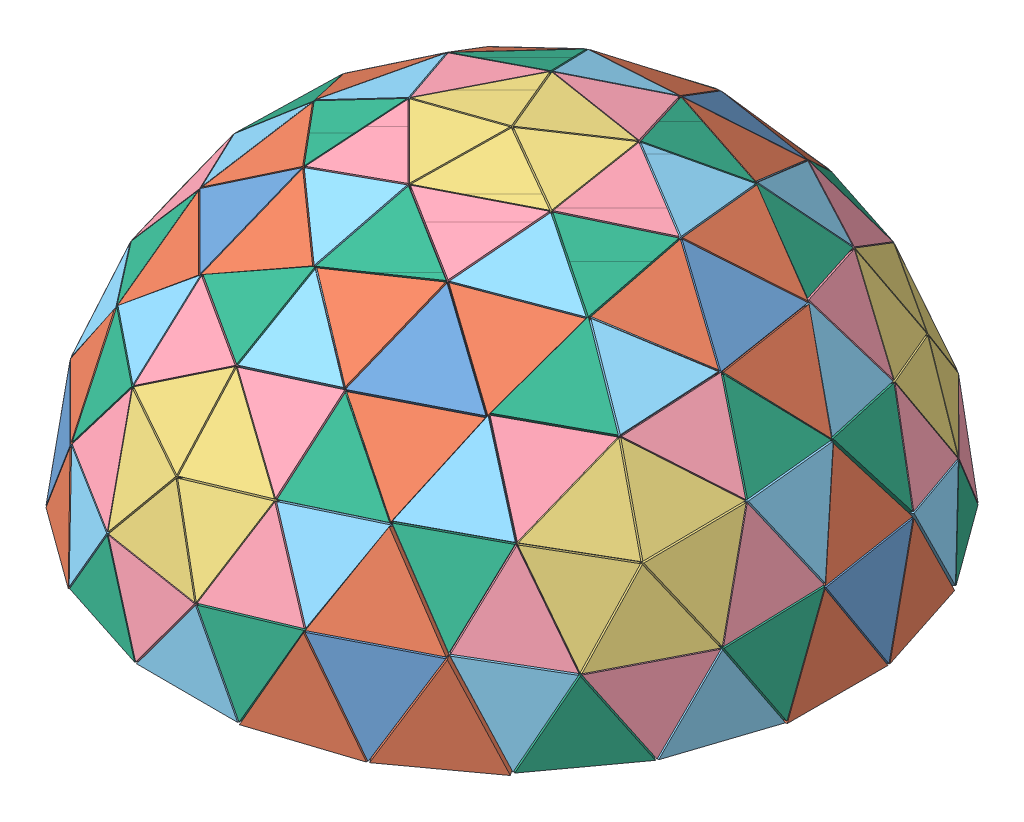
SolidWorks assembly 4Vcorrection, configuration Default. Lengths in mm.
Overall size (6989.16 6215.13 7052.19).
240 component instances, 6 part files, 18 mates.
Components (placement in the parent):
- CCC^4Vcorrection-1: CCC^4Vcorrection [Default] at (5148.8544 1241.364 -148.3819) x (0.61992 0.559911 0.549726) z (-0.217119 -0.550832 0.805881) size (736.35 730.41 804.84) (virtual)
- AAC^4Vcorrection-1: AAC^4Vcorrection [Default] at (1003.1437 19.7447 -1471.5178) x (-0.000489 -0.000047 -1) z (0.99533 0.09653 -0.000491) size (938.64 833.07 70.46) (virtual)
- FFE^4Vcorrection-1: FFE^4Vcorrection [Default] at (-5600.516 7252.777 -2822.5483) x (0.186193 0.133009 -0.973469) z (0.267365 0.946545 0.180468) size (827.41 790.19 223.03) (virtual)
- BBE^4Vcorrection-1: BBE^4Vcorrection [Default] at (-5187.0728 4686.9327 1618.959) x (-0.998714 -0.045499 -0.022385) z (0.046496 -0.997846 -0.046278) size (860.32 848.63 285.86) (virtual)
- ABD^4Vcorrection-2: ABD^4Vcorrection [Default] at (-8587.5048 5777.0189 2775.2885) x (-0.624268 -0.021342 0.780919) z (0.059066 -0.998055 0.019942) size (875.87 755.47 445.29) (virtual)
- ABD_MIRROR^4Vcorrection-1: ABD_MIRROR^4Vcorrection [Default] at (1402.3648 4874.5263 -349.4587) x (0.99908 -0.011123 -0.041412) z (0.039506 0.61429 0.788091) size (875.59 768.38 441.84) (virtual)
- CCC^4Vcorrection-31: CCC^4Vcorrection [Default] at (1449.9639 1241.364 -4942.7041) x (0.714386 0.559911 -0.419705) z (0.699345 -0.550832 0.455523) size (736.35 730.41 804.84) (virtual)
- CCC^4Vcorrection-32: CCC^4Vcorrection [Default] at (-4252.7274 1241.364 -2906.3772) x (-0.178406 0.559911 -0.809117) z (0.649338 -0.550832 -0.524352) size (736.35 730.41 804.84) (virtual)
- CCC^4Vcorrection-33: CCC^4Vcorrection [Default] at (-4078.294 1241.364 3146.4642) x (-0.824647 0.559911 -0.080357) z (-0.298032 -0.550832 -0.779591) size (736.35 730.41 804.84) (virtual)
- CCC^4Vcorrection-34: CCC^4Vcorrection [Default] at (1732.2031 1241.364 4850.999) x (-0.331254 0.559911 0.759454) z (-0.833532 -0.550832 0.042538) size (736.35 730.41 804.84) (virtual)
- AAC^4Vcorrection-101: AAC^4Vcorrection [Default] at (1485.5308 -774.2041 604.8619) x (0.385614 -0.797118 0.464656) z (0.921236 0.360604 -0.145909) size (938.64 833.07 70.46) (virtual)
- AAC^4Vcorrection-130: AAC^4Vcorrection [Default] at (1012.6606 1431.4903 312.0988) x (0.060682 0.883368 0.464735) z (0.946767 0.09653 -0.307106) size (938.64 833.07 70.46) (virtual)
- AAC^4Vcorrection-131: AAC^4Vcorrection [Default] at (1611.8244 210.7493 -727.7764) x (0.701451 -0.406472 -0.585445) z (0.543824 0.836189 0.07102) size (938.64 833.07 70.46) (virtual)
- CCC^4Vcorrection-26: CCC^4Vcorrection [Default] at (3250.1059 4014.1834 -1181.8827) x (0.626993 0.22033 -0.747217) z (-0.756223 -0.058225 -0.651719) size (736.35 730.41 804.84) (virtual)
- AAC^4Vcorrection-104: AAC^4Vcorrection [Default] at (-207.4568 1573.9434 -807.289) x (-0.649291 0.632125 -0.422893) z (0.730552 0.672982 -0.115708) size (938.64 833.07 70.46) (virtual)
- AAC^4Vcorrection-140: AAC^4Vcorrection [Default] at (759.5765 1083.2561 1192.3303) x (0.223363 0.139508 0.9647) z (0.495261 0.836189 -0.235595) size (938.64 833.07 70.46) (virtual)
- AAC^4Vcorrection-136: AAC^4Vcorrection [Default] at (609.753 1431.4903 -866.6536) x (0.460741 0.883368 0.085899) z (0.000491 0.09653 -0.99533) size (938.64 833.07 70.46) (virtual)
- AAC^4Vcorrection-137: AAC^4Vcorrection [Default] at (-635.8125 1431.4903 -847.7202) x (0.224072 0.883368 -0.411646) z (-0.946463 0.09653 -0.308041) size (938.64 833.07 70.46) (virtual)
- AAC^4Vcorrection-138: AAC^4Vcorrection [Default] at (-1002.7067 1431.4903 342.7337) x (-0.322257 0.883368 -0.340311) z (-0.585438 0.09653 0.80495) size (938.64 833.07 70.46) (virtual)
- AAC^4Vcorrection-139: AAC^4Vcorrection [Default] at (16.1057 1431.4903 1059.5413) x (-0.423238 0.883368 0.201323) z (0.584643 0.09653 0.805528) size (938.64 833.07 70.46) (virtual)
- AAC^4Vcorrection-126: AAC^4Vcorrection [Default] at (1034.3121 -774.2041 -1225.9111) x (0.561075 -0.797118 -0.223154) z (0.145909 0.360604 -0.921236) size (938.64 833.07 70.46) (virtual)
- AAC^4Vcorrection-127: AAC^4Vcorrection [Default] at (-846.2907 -774.2041 -1362.5167) x (-0.03885 -0.797118 -0.602573) z (-0.831059 0.360604 -0.423446) size (938.64 833.07 70.46) (virtual)
- AAC^4Vcorrection-128: AAC^4Vcorrection [Default] at (-1557.3486 -774.2041 383.8295) x (-0.585086 -0.797118 -0.149256) z (-0.659532 0.360604 0.659532) size (938.64 833.07 70.46) (virtual)
- AAC^4Vcorrection-129: AAC^4Vcorrection [Default] at (-116.2036 -774.2041 1599.7364) x (-0.322753 -0.797118 0.510327) z (0.423446 0.360604 0.831059) size (938.64 833.07 70.46) (virtual)
- AAC^4Vcorrection-145: AAC^4Vcorrection [Default] at (-1089.5081 19.7447 -1408.7704) x (-0.951208 -0.000047 -0.308552) z (0.307106 0.09653 -0.946767) size (938.64 833.07 70.46) (virtual)
- AAC^4Vcorrection-146: AAC^4Vcorrection [Default] at (-1676.4968 19.7447 600.8498) x (-0.587389 -0.000047 0.809304) z (-0.805528 0.09653 -0.584643) size (938.64 833.07 70.46) (virtual)
- AAC^4Vcorrection-147: AAC^4Vcorrection [Default] at (53.3761 19.7447 1780.116) x (0.588181 -0.000047 0.808729) z (-0.80495 0.09653 0.585438) size (938.64 833.07 70.46) (virtual)
- AAC^4Vcorrection-148: AAC^4Vcorrection [Default] at (1709.485 19.7447 499.3224) x (0.950905 -0.000047 -0.309482) z (0.308041 0.09653 0.946463) size (938.64 833.07 70.46) (virtual)
- AAC^4Vcorrection-132: AAC^4Vcorrection [Default] at (-194.0754 210.7493 -1757.8314) x (-0.340031 -0.406472 -0.848032) z (0.235595 0.836189 -0.495261) size (938.64 833.07 70.46) (virtual)
- AAC^4Vcorrection-133: AAC^4Vcorrection [Default] at (-1731.7696 210.7493 -358.6231) x (-0.911602 -0.406472 0.061332) z (-0.398218 0.836189 -0.377108) size (938.64 833.07 70.46) (virtual)
- AAC^4Vcorrection-134: AAC^4Vcorrection [Default] at (-876.2171 210.7493 1536.1901) x (-0.22337 -0.406472 0.885938) z (-0.481707 0.836189 0.262195) size (938.64 833.07 70.46) (virtual)
- AAC^4Vcorrection-135: AAC^4Vcorrection [Default] at (1190.2376 210.7493 1308.0408) x (0.773552 -0.406472 0.486207) z (0.100507 0.836189 0.539154) size (938.64 833.07 70.46) (virtual)
- CCC^4Vcorrection-27: CCC^4Vcorrection [Default] at (-119.6993 4014.1834 -3456.2562) x (-0.516894 0.22033 -0.827209) z (-0.853507 -0.058225 0.517818) size (736.35 730.41 804.84) (virtual)
- CCC^4Vcorrection-28: CCC^4Vcorrection [Default] at (-3324.0841 4014.1834 -954.2011) x (-0.946452 0.22033 0.235974) z (0.228726 -0.058225 0.971748) size (736.35 730.41 804.84) (virtual)
- CCC^4Vcorrection-29: CCC^4Vcorrection [Default] at (-1934.6977 4014.1834 2866.5275) x (-0.068045 0.22033 0.973049) z (0.994868 -0.058225 0.082755) size (736.35 730.41 804.84) (virtual)
- CCC^4Vcorrection-30: CCC^4Vcorrection [Default] at (2128.3752 4014.1834 2725.8125) x (0.904398 0.22033 0.365403) z (0.386136 -0.058225 -0.920603) size (736.35 730.41 804.84) (virtual)
- AAC^4Vcorrection-122: AAC^4Vcorrection [Default] at (-831.8851 1573.9434 -52.1629) x (-0.602838 0.632125 0.486832) z (0.115708 0.672982 -0.730552) size (938.64 833.07 70.46) (virtual)
- AAC^4Vcorrection-123: AAC^4Vcorrection [Default] at (-306.6765 1573.9434 775.0505) x (0.276717 0.632125 0.723772) z (-0.659041 0.672982 -0.335798) size (938.64 833.07 70.46) (virtual)
- AAC^4Vcorrection-124: AAC^4Vcorrection [Default] at (642.3486 1573.9434 531.1705) x (0.773858 0.632125 -0.039516) z (-0.523018 0.672982 0.523018) size (938.64 833.07 70.46) (virtual)
- AAC^4Vcorrection-125: AAC^4Vcorrection [Default] at (703.6698 1573.9434 -446.7691) x (0.201554 0.632125 -0.748194) z (0.335798 0.672982 0.659041) size (938.64 833.07 70.46) (virtual)
- AAC^4Vcorrection-141: AAC^4Vcorrection [Default] at (1368.6955 1083.2561 -353.9498) x (0.986507 0.139508 0.085677) z (-0.07102 0.836189 -0.543824) size (938.64 833.07 70.46) (virtual)
- AAC^4Vcorrection-142: AAC^4Vcorrection [Default] at (86.3239 1083.2561 -1411.0833) x (0.386332 0.139508 -0.911748) z (-0.539154 0.836189 -0.100507) size (938.64 833.07 70.46) (virtual)
- AAC^4Vcorrection-143: AAC^4Vcorrection [Default] at (-1315.3444 1083.2561 -518.1476) x (-0.747741 0.139508 -0.649169) z (-0.262195 0.836189 0.481707) size (938.64 833.07 70.46) (virtual)
- AAC^4Vcorrection-144: AAC^4Vcorrection [Default] at (-899.2515 1083.2561 1090.8505) x (-0.848461 0.139508 0.51054) z (0.377108 0.836189 0.398218) size (938.64 833.07 70.46) (virtual)
- ABD^4Vcorrection-53: ABD^4Vcorrection [Default] at (-14.2287 5777.0189 9024.8137) x (0.549789 -0.021342 0.835031) z (0.037218 -0.998055 -0.050013) size (875.87 755.47 445.29) (virtual)
- ABD^4Vcorrection-114: ABD^4Vcorrection [Default] at (8578.711 5777.0189 2802.3531) x (0.964056 -0.021342 -0.264841) z (-0.036064 -0.998055 -0.050851) size (875.87 755.47 445.29) (virtual)
- ABD^4Vcorrection-124: ABD^4Vcorrection [Default] at (5316.1637 5777.0189 -7292.8643) x (0.04603 -0.021342 -0.998712) z (-0.059507 -0.998055 0.018585) size (875.87 755.47 445.29) (virtual)
- ABD^4Vcorrection-134: ABD^4Vcorrection [Default] at (-5293.1411 5777.0189 -7309.5911) x (-0.935607 -0.021342 -0.352396) z (-0.000713 -0.998055 0.062338) size (875.87 755.47 445.29) (virtual)
- ABD_MIRROR^4Vcorrection-37: ABD_MIRROR^4Vcorrection [Default] at (100.9996 4874.5263 -1441.7169) x (0.269347 -0.011123 -0.962979) z (0.761727 0.61429 0.205961) size (875.59 768.38 441.84) (virtual)
- ABD_MIRROR^4Vcorrection-98: ABD_MIRROR^4Vcorrection [Default] at (-1339.9436 4874.5263 -541.5713) x (-0.832614 -0.011123 -0.553741) z (0.431267 0.61429 -0.660799) size (875.59 768.38 441.84) (virtual)
- ABD_MIRROR^4Vcorrection-108: ABD_MIRROR^4Vcorrection [Default] at (-929.1303 4874.5263 1107.0074) x (-0.783931 -0.011123 0.620748) z (-0.495189 0.61429 -0.614358) size (875.59 768.38 441.84) (virtual)
- ABD_MIRROR^4Vcorrection-118: ABD_MIRROR^4Vcorrection [Default] at (765.7096 4874.5263 1225.7395) x (0.348118 -0.011123 0.937385) z (-0.737311 0.61429 0.281105) size (875.59 768.38 441.84) (virtual)
- BBE^4Vcorrection-31: BBE^4Vcorrection [Default] at (-63.1721 4686.9327 5433.4852) x (-0.329909 -0.045499 0.942916) z (-0.029645 -0.997846 -0.058521) size (860.32 848.63 285.86) (virtual)
- BBE^4Vcorrection-92: BBE^4Vcorrection [Default] at (5148.0302 4686.9327 1739.1195) x (0.794819 -0.045499 0.605139) z (-0.064818 -0.997846 0.01011) size (860.32 848.63 285.86) (virtual)
- BBE^4Vcorrection-102: BBE^4Vcorrection [Default] at (3244.8298 4686.9327 -4358.6502) x (0.821134 -0.045499 -0.568919) z (-0.010415 -0.997846 0.064769) size (860.32 848.63 285.86) (virtual)
- BBE^4Vcorrection-112: BBE^4Vcorrection [Default] at (-3142.6151 4686.9327 -4432.9135) x (-0.28733 -0.045499 -0.95675) z (0.058381 -0.997846 0.02992) size (860.32 848.63 285.86) (virtual)
- FFE^4Vcorrection-27: FFE^4Vcorrection [Default] at (-4415.0576 7252.777 4454.1919) x (-0.868287 0.133009 -0.477898) z (0.254256 0.946545 -0.198512) size (827.41 790.19 223.03) (virtual)
- FFE^4Vcorrection-88: FFE^4Vcorrection [Default] at (2871.8604 7252.777 5575.3903) x (-0.722823 0.133009 0.678111) z (-0.110226 0.946545 -0.303155) size (827.41 790.19 223.03) (virtual)
- FFE^4Vcorrection-98: FFE^4Vcorrection [Default] at (6189.9649 7252.777 -1008.4112) x (0.421558 0.133009 0.896994) z (-0.322379 0.946545 0.011151) size (827.41 790.19 223.03) (virtual)
- FFE^4Vcorrection-108: FFE^4Vcorrection [Default] at (953.7484 7252.777 -6198.6227) x (0.98336 0.133009 -0.123739) z (-0.089015 0.946545 0.310047) size (827.41 790.19 223.03) (virtual)
- ABD^4Vcorrection-144: ABD^4Vcorrection [Default] at (7466.3779 6226.7147 4505.8449) x (0.554978 0.76321 -0.330922) z (0.075466 -0.442359 -0.893657) size (875.87 755.47 445.29) (virtual)
- ABD_MIRROR^4Vcorrection-128: ABD_MIRROR^4Vcorrection [Default] at (-2017.2487 1708.941 4342.8083) x (-0.981501 -0.177094 -0.072755) z (-0.187221 0.967276 0.171244) size (875.59 768.38 441.84) (virtual)
- BBE^4Vcorrection-122: BBE^4Vcorrection [Default] at (4352.124 4252.7353 3803.5969) x (0.994073 0.095186 0.052524) z (0.093298 -0.498914 -0.861615) size (860.32 848.63 285.86) (virtual)
- FFE^4Vcorrection-118: FFE^4Vcorrection [Default] at (4777.7299 1556.6671 8166.114) x (-0.121759 -0.822885 0.555008) z (-0.407266 0.551349 0.728113) size (827.41 790.19 223.03) (virtual)
- ABD^4Vcorrection-78: ABD^4Vcorrection [Default] at (-1512.6158 10570.6712 891.2438) x (-0.608653 0.651589 -0.452741) z (0.102795 -0.501041 -0.859297) size (875.87 755.47 445.29) (virtual)
- ABD^4Vcorrection-115: ABD^4Vcorrection [Default] at (-9484.5166 3921.3023 3080.3808) x (-0.927145 -0.373861 0.025123) z (0.175217 -0.491836 -0.852875) size (875.87 755.47 445.29) (virtual)
- ABD^4Vcorrection-125: ABD^4Vcorrection [Default] at (-5432.4284 -4532.1902 8047.943) x (0.039648 -0.896002 0.442277) z (0.192648 -0.427466 -0.883267) size (875.87 755.47 445.29) (virtual)
- ABD^4Vcorrection-135: ABD^4Vcorrection [Default] at (5043.8005 -3107.3671 8928.9282) x (0.95565 -0.193254 0.222229) z (0.130998 -0.396887 -0.908471) size (875.87 755.47 445.29) (virtual)
- ABD_MIRROR^4Vcorrection-62: ABD_MIRROR^4Vcorrection [Default] at (-642.4774 922.9937 4958.3325) x (-0.185167 -0.890187 0.416269) z (-0.852377 0.356291 0.382767) size (875.59 768.38 441.84) (virtual)
- ABD_MIRROR^4Vcorrection-99: ABD_MIRROR^4Vcorrection [Default] at (706.1181 1911.7465 4657.9371) x (0.869148 -0.380032 0.316477) z (-0.454767 -0.362683 0.813418) size (875.59 768.38 441.84) (virtual)
- ABD_MIRROR^4Vcorrection-109: ABD_MIRROR^4Vcorrection [Default] at (164.8246 3308.7767 3856.7583) x (0.724415 0.648354 -0.234221) z (0.456126 -0.196048 0.868052) size (875.59 768.38 441.84) (virtual)
- ABD_MIRROR^4Vcorrection-119: ABD_MIRROR^4Vcorrection [Default] at (-1518.3086 3183.436 3661.998) x (-0.419349 0.773777 -0.47478) z (0.621478 0.625912 0.471167) size (875.59 768.38 441.84) (virtual)
- BBE^4Vcorrection-56: BBE^4Vcorrection [Default] at (-1020.7958 6918.9452 1606.3199) x (0.254295 0.855087 -0.451842) z (0.169482 -0.499371 -0.849649) size (860.32 848.63 285.86) (virtual)
- BBE^4Vcorrection-93: BBE^4Vcorrection [Default] at (-5861.8912 2956.2669 2897.0343) x (-0.828378 0.404815 -0.387187) z (0.198561 -0.434119 -0.8787) size (860.32 848.63 285.86) (virtual)
- BBE^4Vcorrection-103: BBE^4Vcorrection [Default] at (-3480.9329 -2159.0128 5892.0166) x (-0.757729 -0.633368 0.157138) z (0.140348 -0.393334 -0.90862) size (860.32 848.63 285.86) (virtual)
- BBE^4Vcorrection-113: BBE^4Vcorrection [Default] at (2831.6756 -1357.7513 6452.3031) x (0.368608 -0.824729 0.428894) z (0.075293 -0.433379 -0.898061) size (860.32 848.63 285.86) (virtual)
- FFE^4Vcorrection-52: FFE^4Vcorrection [Default] at (3008.3825 7808.2776 4681.4281) x (0.878569 -0.243094 0.411123) z (-0.363131 0.219161 0.905596) size (827.41 790.19 223.03) (virtual)
- FFE^4Vcorrection-89: FFE^4Vcorrection [Default] at (-4278.4681 7807.5557 3559.7918) x (0.639803 0.755876 -0.138939) z (0.005345 0.176402 0.984304) size (827.41 790.19 223.03) (virtual)
- FFE^4Vcorrection-99: FFE^4Vcorrection [Default] at (-7012.6419 1555.4991 6351.2683) x (-0.50809 0.793481 -0.335011) z (0.188941 0.482164 0.855464) size (827.41 790.19 223.03) (virtual)
- FFE^4Vcorrection-109: FFE^4Vcorrection [Default] at (-1415.6037 -2307.7625 9198.132) x (-0.978762 -0.182247 0.093872) z (-0.066067 0.713895 0.69713) size (827.41 790.19 223.03) (virtual)
- ABD^4Vcorrection-149: ABD^4Vcorrection [Default] at (-14.2287 5777.0189 9024.8137) x (0.549789 -0.021342 0.835031) z (0.037218 -0.998055 -0.050013) size (875.87 755.47 445.29) (virtual)
- ABD^4Vcorrection-150: ABD^4Vcorrection [Default] at (8578.711 5777.0189 2802.3531) x (0.964056 -0.021342 -0.264841) z (-0.036064 -0.998055 -0.050851) size (875.87 755.47 445.29) (virtual)
- ABD^4Vcorrection-151: ABD^4Vcorrection [Default] at (5316.1637 5777.0189 -7292.8643) x (0.04603 -0.021342 -0.998712) z (-0.059507 -0.998055 0.018585) size (875.87 755.47 445.29) (virtual)
- ABD^4Vcorrection-152: ABD^4Vcorrection [Default] at (-5293.1411 5777.0189 -7309.5911) x (-0.935607 -0.021342 -0.352396) z (-0.000713 -0.998055 0.062338) size (875.87 755.47 445.29) (virtual)
- ABD_MIRROR^4Vcorrection-133: ABD_MIRROR^4Vcorrection [Default] at (100.9996 4874.5263 -1441.7169) x (0.269347 -0.011123 -0.962979) z (0.761727 0.61429 0.205961) size (875.59 768.38 441.84) (virtual)
- ABD_MIRROR^4Vcorrection-134: ABD_MIRROR^4Vcorrection [Default] at (-1339.9436 4874.5263 -541.5713) x (-0.832614 -0.011123 -0.553741) z (0.431267 0.61429 -0.660799) size (875.59 768.38 441.84) (virtual)
- ABD_MIRROR^4Vcorrection-135: ABD_MIRROR^4Vcorrection [Default] at (-929.1303 4874.5263 1107.0074) x (-0.783931 -0.011123 0.620748) z (-0.495189 0.61429 -0.614358) size (875.59 768.38 441.84) (virtual)
- ABD_MIRROR^4Vcorrection-136: ABD_MIRROR^4Vcorrection [Default] at (765.7096 4874.5263 1225.7395) x (0.348118 -0.011123 0.937385) z (-0.737311 0.61429 0.281105) size (875.59 768.38 441.84) (virtual)
- BBE^4Vcorrection-127: BBE^4Vcorrection [Default] at (-63.1721 4686.9327 5433.4852) x (-0.329909 -0.045499 0.942916) z (-0.029645 -0.997846 -0.058521) size (860.32 848.63 285.86) (virtual)
- BBE^4Vcorrection-128: BBE^4Vcorrection [Default] at (5148.0302 4686.9327 1739.1195) x (0.794819 -0.045499 0.605139) z (-0.064818 -0.997846 0.01011) size (860.32 848.63 285.86) (virtual)
- BBE^4Vcorrection-129: BBE^4Vcorrection [Default] at (3244.8298 4686.9327 -4358.6502) x (0.821134 -0.045499 -0.568919) z (-0.010415 -0.997846 0.064769) size (860.32 848.63 285.86) (virtual)
- BBE^4Vcorrection-130: BBE^4Vcorrection [Default] at (-3142.6151 4686.9327 -4432.9135) x (-0.28733 -0.045499 -0.95675) z (0.058381 -0.997846 0.02992) size (860.32 848.63 285.86) (virtual)
- FFE^4Vcorrection-123: FFE^4Vcorrection [Default] at (-4415.0576 7252.777 4454.1919) x (-0.868287 0.133009 -0.477898) z (0.254256 0.946545 -0.198512) size (827.41 790.19 223.03) (virtual)
- FFE^4Vcorrection-124: FFE^4Vcorrection [Default] at (2871.8604 7252.777 5575.3903) x (-0.722823 0.133009 0.678111) z (-0.110226 0.946545 -0.303155) size (827.41 790.19 223.03) (virtual)
- FFE^4Vcorrection-125: FFE^4Vcorrection [Default] at (6189.9649 7252.777 -1008.4112) x (0.421558 0.133009 0.896994) z (-0.322379 0.946545 0.011151) size (827.41 790.19 223.03) (virtual)
- FFE^4Vcorrection-126: FFE^4Vcorrection [Default] at (953.7484 7252.777 -6198.6227) x (0.98336 0.133009 -0.123739) z (-0.089015 0.946545 0.310047) size (827.41 790.19 223.03) (virtual)
- ABD^4Vcorrection-110: ABD^4Vcorrection [Default] at (8578.711 5777.0189 2802.3531) x (0.964056 -0.021342 -0.264841) z (-0.036064 -0.998055 -0.050851) size (875.87 755.47 445.29) (virtual)
- ABD^4Vcorrection-111: ABD^4Vcorrection [Default] at (5316.1637 5777.0189 -7292.8643) x (0.04603 -0.021342 -0.998712) z (-0.059507 -0.998055 0.018585) size (875.87 755.47 445.29) (virtual)
- ABD^4Vcorrection-112: ABD^4Vcorrection [Default] at (-5293.1411 5777.0189 -7309.5911) x (-0.935607 -0.021342 -0.352396) z (-0.000713 -0.998055 0.062338) size (875.87 755.47 445.29) (virtual)
- ABD^4Vcorrection-113: ABD^4Vcorrection [Default] at (-8587.5048 5777.0189 2775.2885) x (-0.624268 -0.021342 0.780919) z (0.059066 -0.998055 0.019942) size (875.87 755.47 445.29) (virtual)
- ABD^4Vcorrection-120: ABD^4Vcorrection [Default] at (5316.1637 5777.0189 -7292.8643) x (0.04603 -0.021342 -0.998712) z (-0.059507 -0.998055 0.018585) size (875.87 755.47 445.29) (virtual)
- ABD^4Vcorrection-121: ABD^4Vcorrection [Default] at (-5293.1411 5777.0189 -7309.5911) x (-0.935607 -0.021342 -0.352396) z (-0.000713 -0.998055 0.062338) size (875.87 755.47 445.29) (virtual)
- ABD^4Vcorrection-122: ABD^4Vcorrection [Default] at (-8587.5048 5777.0189 2775.2885) x (-0.624268 -0.021342 0.780919) z (0.059066 -0.998055 0.019942) size (875.87 755.47 445.29) (virtual)
- ABD^4Vcorrection-123: ABD^4Vcorrection [Default] at (-14.2287 5777.0189 9024.8137) x (0.549789 -0.021342 0.835031) z (0.037218 -0.998055 -0.050013) size (875.87 755.47 445.29) (virtual)
- ABD^4Vcorrection-130: ABD^4Vcorrection [Default] at (-5293.1411 5777.0189 -7309.5911) x (-0.935607 -0.021342 -0.352396) z (-0.000713 -0.998055 0.062338) size (875.87 755.47 445.29) (virtual)
- ABD^4Vcorrection-131: ABD^4Vcorrection [Default] at (-8587.5048 5777.0189 2775.2885) x (-0.624268 -0.021342 0.780919) z (0.059066 -0.998055 0.019942) size (875.87 755.47 445.29) (virtual)
- ABD^4Vcorrection-132: ABD^4Vcorrection [Default] at (-14.2287 5777.0189 9024.8137) x (0.549789 -0.021342 0.835031) z (0.037218 -0.998055 -0.050013) size (875.87 755.47 445.29) (virtual)
- ABD^4Vcorrection-133: ABD^4Vcorrection [Default] at (8578.711 5777.0189 2802.3531) x (0.964056 -0.021342 -0.264841) z (-0.036064 -0.998055 -0.050851) size (875.87 755.47 445.29) (virtual)
- ABD^4Vcorrection-140: ABD^4Vcorrection [Default] at (-8587.5048 5777.0189 2775.2885) x (-0.624268 -0.021342 0.780919) z (0.059066 -0.998055 0.019942) size (875.87 755.47 445.29) (virtual)
- ABD^4Vcorrection-141: ABD^4Vcorrection [Default] at (-14.2287 5777.0189 9024.8137) x (0.549789 -0.021342 0.835031) z (0.037218 -0.998055 -0.050013) size (875.87 755.47 445.29) (virtual)
- ABD^4Vcorrection-142: ABD^4Vcorrection [Default] at (8578.711 5777.0189 2802.3531) x (0.964056 -0.021342 -0.264841) z (-0.036064 -0.998055 -0.050851) size (875.87 755.47 445.29) (virtual)
- ABD^4Vcorrection-143: ABD^4Vcorrection [Default] at (5316.1637 5777.0189 -7292.8643) x (0.04603 -0.021342 -0.998712) z (-0.059507 -0.998055 0.018585) size (875.87 755.47 445.29) (virtual)
- ABD_MIRROR^4Vcorrection-94: ABD_MIRROR^4Vcorrection [Default] at (-1339.9436 4874.5263 -541.5713) x (-0.832614 -0.011123 -0.553741) z (0.431267 0.61429 -0.660799) size (875.59 768.38 441.84) (virtual)
- ABD_MIRROR^4Vcorrection-95: ABD_MIRROR^4Vcorrection [Default] at (-929.1303 4874.5263 1107.0074) x (-0.783931 -0.011123 0.620748) z (-0.495189 0.61429 -0.614358) size (875.59 768.38 441.84) (virtual)
- ABD_MIRROR^4Vcorrection-96: ABD_MIRROR^4Vcorrection [Default] at (765.7096 4874.5263 1225.7395) x (0.348118 -0.011123 0.937385) z (-0.737311 0.61429 0.281105) size (875.59 768.38 441.84) (virtual)
- ABD_MIRROR^4Vcorrection-97: ABD_MIRROR^4Vcorrection [Default] at (1402.3648 4874.5263 -349.4587) x (0.99908 -0.011123 -0.041412) z (0.039506 0.61429 0.788091) size (875.59 768.38 441.84) (virtual)
- ABD_MIRROR^4Vcorrection-104: ABD_MIRROR^4Vcorrection [Default] at (-929.1303 4874.5263 1107.0074) x (-0.783931 -0.011123 0.620748) z (-0.495189 0.61429 -0.614358) size (875.59 768.38 441.84) (virtual)
- ABD_MIRROR^4Vcorrection-105: ABD_MIRROR^4Vcorrection [Default] at (765.7096 4874.5263 1225.7395) x (0.348118 -0.011123 0.937385) z (-0.737311 0.61429 0.281105) size (875.59 768.38 441.84) (virtual)
- ABD_MIRROR^4Vcorrection-106: ABD_MIRROR^4Vcorrection [Default] at (1402.3648 4874.5263 -349.4587) x (0.99908 -0.011123 -0.041412) z (0.039506 0.61429 0.788091) size (875.59 768.38 441.84) (virtual)
- ABD_MIRROR^4Vcorrection-107: ABD_MIRROR^4Vcorrection [Default] at (100.9996 4874.5263 -1441.7169) x (0.269347 -0.011123 -0.962979) z (0.761727 0.61429 0.205961) size (875.59 768.38 441.84) (virtual)
- ABD_MIRROR^4Vcorrection-114: ABD_MIRROR^4Vcorrection [Default] at (765.7096 4874.5263 1225.7395) x (0.348118 -0.011123 0.937385) z (-0.737311 0.61429 0.281105) size (875.59 768.38 441.84) (virtual)
- ABD_MIRROR^4Vcorrection-115: ABD_MIRROR^4Vcorrection [Default] at (1402.3648 4874.5263 -349.4587) x (0.99908 -0.011123 -0.041412) z (0.039506 0.61429 0.788091) size (875.59 768.38 441.84) (virtual)
- ABD_MIRROR^4Vcorrection-116: ABD_MIRROR^4Vcorrection [Default] at (100.9996 4874.5263 -1441.7169) x (0.269347 -0.011123 -0.962979) z (0.761727 0.61429 0.205961) size (875.59 768.38 441.84) (virtual)
- ABD_MIRROR^4Vcorrection-117: ABD_MIRROR^4Vcorrection [Default] at (-1339.9436 4874.5263 -541.5713) x (-0.832614 -0.011123 -0.553741) z (0.431267 0.61429 -0.660799) size (875.59 768.38 441.84) (virtual)
- ABD_MIRROR^4Vcorrection-124: ABD_MIRROR^4Vcorrection [Default] at (1402.3648 4874.5263 -349.4587) x (0.99908 -0.011123 -0.041412) z (0.039506 0.61429 0.788091) size (875.59 768.38 441.84) (virtual)
- ABD_MIRROR^4Vcorrection-125: ABD_MIRROR^4Vcorrection [Default] at (100.9996 4874.5263 -1441.7169) x (0.269347 -0.011123 -0.962979) z (0.761727 0.61429 0.205961) size (875.59 768.38 441.84) (virtual)
- ABD_MIRROR^4Vcorrection-126: ABD_MIRROR^4Vcorrection [Default] at (-1339.9436 4874.5263 -541.5713) x (-0.832614 -0.011123 -0.553741) z (0.431267 0.61429 -0.660799) size (875.59 768.38 441.84) (virtual)
- ABD_MIRROR^4Vcorrection-127: ABD_MIRROR^4Vcorrection [Default] at (-929.1303 4874.5263 1107.0074) x (-0.783931 -0.011123 0.620748) z (-0.495189 0.61429 -0.614358) size (875.59 768.38 441.84) (virtual)
- BBE^4Vcorrection-88: BBE^4Vcorrection [Default] at (5148.0302 4686.9327 1739.1195) x (0.794819 -0.045499 0.605139) z (-0.064818 -0.997846 0.01011) size (860.32 848.63 285.86) (virtual)
- BBE^4Vcorrection-89: BBE^4Vcorrection [Default] at (3244.8298 4686.9327 -4358.6502) x (0.821134 -0.045499 -0.568919) z (-0.010415 -0.997846 0.064769) size (860.32 848.63 285.86) (virtual)
- BBE^4Vcorrection-90: BBE^4Vcorrection [Default] at (-3142.6151 4686.9327 -4432.9135) x (-0.28733 -0.045499 -0.95675) z (0.058381 -0.997846 0.02992) size (860.32 848.63 285.86) (virtual)
- BBE^4Vcorrection-91: BBE^4Vcorrection [Default] at (-5187.0728 4686.9327 1618.959) x (-0.998714 -0.045499 -0.022385) z (0.046496 -0.997846 -0.046278) size (860.32 848.63 285.86) (virtual)
- BBE^4Vcorrection-98: BBE^4Vcorrection [Default] at (3244.8298 4686.9327 -4358.6502) x (0.821134 -0.045499 -0.568919) z (-0.010415 -0.997846 0.064769) size (860.32 848.63 285.86) (virtual)
- BBE^4Vcorrection-99: BBE^4Vcorrection [Default] at (-3142.6151 4686.9327 -4432.9135) x (-0.28733 -0.045499 -0.95675) z (0.058381 -0.997846 0.02992) size (860.32 848.63 285.86) (virtual)
- BBE^4Vcorrection-100: BBE^4Vcorrection [Default] at (-5187.0728 4686.9327 1618.959) x (-0.998714 -0.045499 -0.022385) z (0.046496 -0.997846 -0.046278) size (860.32 848.63 285.86) (virtual)
- BBE^4Vcorrection-101: BBE^4Vcorrection [Default] at (-63.1721 4686.9327 5433.4852) x (-0.329909 -0.045499 0.942916) z (-0.029645 -0.997846 -0.058521) size (860.32 848.63 285.86) (virtual)
- BBE^4Vcorrection-108: BBE^4Vcorrection [Default] at (-3142.6151 4686.9327 -4432.9135) x (-0.28733 -0.045499 -0.95675) z (0.058381 -0.997846 0.02992) size (860.32 848.63 285.86) (virtual)
- BBE^4Vcorrection-109: BBE^4Vcorrection [Default] at (-5187.0728 4686.9327 1618.959) x (-0.998714 -0.045499 -0.022385) z (0.046496 -0.997846 -0.046278) size (860.32 848.63 285.86) (virtual)
- BBE^4Vcorrection-110: BBE^4Vcorrection [Default] at (-63.1721 4686.9327 5433.4852) x (-0.329909 -0.045499 0.942916) z (-0.029645 -0.997846 -0.058521) size (860.32 848.63 285.86) (virtual)
- BBE^4Vcorrection-111: BBE^4Vcorrection [Default] at (5148.0302 4686.9327 1739.1195) x (0.794819 -0.045499 0.605139) z (-0.064818 -0.997846 0.01011) size (860.32 848.63 285.86) (virtual)
- BBE^4Vcorrection-118: BBE^4Vcorrection [Default] at (-5187.0728 4686.9327 1618.959) x (-0.998714 -0.045499 -0.022385) z (0.046496 -0.997846 -0.046278) size (860.32 848.63 285.86) (virtual)
- BBE^4Vcorrection-119: BBE^4Vcorrection [Default] at (-63.1721 4686.9327 5433.4852) x (-0.329909 -0.045499 0.942916) z (-0.029645 -0.997846 -0.058521) size (860.32 848.63 285.86) (virtual)
- BBE^4Vcorrection-120: BBE^4Vcorrection [Default] at (5148.0302 4686.9327 1739.1195) x (0.794819 -0.045499 0.605139) z (-0.064818 -0.997846 0.01011) size (860.32 848.63 285.86) (virtual)
- BBE^4Vcorrection-121: BBE^4Vcorrection [Default] at (3244.8298 4686.9327 -4358.6502) x (0.821134 -0.045499 -0.568919) z (-0.010415 -0.997846 0.064769) size (860.32 848.63 285.86) (virtual)
- FFE^4Vcorrection-84: FFE^4Vcorrection [Default] at (2871.8604 7252.777 5575.3903) x (-0.722823 0.133009 0.678111) z (-0.110226 0.946545 -0.303155) size (827.41 790.19 223.03) (virtual)
- FFE^4Vcorrection-85: FFE^4Vcorrection [Default] at (6189.9649 7252.777 -1008.4112) x (0.421558 0.133009 0.896994) z (-0.322379 0.946545 0.011151) size (827.41 790.19 223.03) (virtual)
- FFE^4Vcorrection-86: FFE^4Vcorrection [Default] at (953.7484 7252.777 -6198.6227) x (0.98336 0.133009 -0.123739) z (-0.089015 0.946545 0.310047) size (827.41 790.19 223.03) (virtual)
- FFE^4Vcorrection-87: FFE^4Vcorrection [Default] at (-5600.516 7252.777 -2822.5483) x (0.186193 0.133009 -0.973469) z (0.267365 0.946545 0.180468) size (827.41 790.19 223.03) (virtual)
- FFE^4Vcorrection-94: FFE^4Vcorrection [Default] at (6189.9649 7252.777 -1008.4112) x (0.421558 0.133009 0.896994) z (-0.322379 0.946545 0.011151) size (827.41 790.19 223.03) (virtual)
- FFE^4Vcorrection-95: FFE^4Vcorrection [Default] at (953.7484 7252.777 -6198.6227) x (0.98336 0.133009 -0.123739) z (-0.089015 0.946545 0.310047) size (827.41 790.19 223.03) (virtual)
- FFE^4Vcorrection-96: FFE^4Vcorrection [Default] at (-5600.516 7252.777 -2822.5483) x (0.186193 0.133009 -0.973469) z (0.267365 0.946545 0.180468) size (827.41 790.19 223.03) (virtual)
- FFE^4Vcorrection-97: FFE^4Vcorrection [Default] at (-4415.0576 7252.777 4454.1919) x (-0.868287 0.133009 -0.477898) z (0.254256 0.946545 -0.198512) size (827.41 790.19 223.03) (virtual)
- FFE^4Vcorrection-104: FFE^4Vcorrection [Default] at (953.7484 7252.777 -6198.6227) x (0.98336 0.133009 -0.123739) z (-0.089015 0.946545 0.310047) size (827.41 790.19 223.03) (virtual)
- FFE^4Vcorrection-105: FFE^4Vcorrection [Default] at (-5600.516 7252.777 -2822.5483) x (0.186193 0.133009 -0.973469) z (0.267365 0.946545 0.180468) size (827.41 790.19 223.03) (virtual)
- FFE^4Vcorrection-106: FFE^4Vcorrection [Default] at (-4415.0576 7252.777 4454.1919) x (-0.868287 0.133009 -0.477898) z (0.254256 0.946545 -0.198512) size (827.41 790.19 223.03) (virtual)
- FFE^4Vcorrection-107: FFE^4Vcorrection [Default] at (2871.8604 7252.777 5575.3903) x (-0.722823 0.133009 0.678111) z (-0.110226 0.946545 -0.303155) size (827.41 790.19 223.03) (virtual)
- FFE^4Vcorrection-114: FFE^4Vcorrection [Default] at (-5600.516 7252.777 -2822.5483) x (0.186193 0.133009 -0.973469) z (0.267365 0.946545 0.180468) size (827.41 790.19 223.03) (virtual)
- FFE^4Vcorrection-115: FFE^4Vcorrection [Default] at (-4415.0576 7252.777 4454.1919) x (-0.868287 0.133009 -0.477898) z (0.254256 0.946545 -0.198512) size (827.41 790.19 223.03) (virtual)
- FFE^4Vcorrection-116: FFE^4Vcorrection [Default] at (2871.8604 7252.777 5575.3903) x (-0.722823 0.133009 0.678111) z (-0.110226 0.946545 -0.303155) size (827.41 790.19 223.03) (virtual)
- FFE^4Vcorrection-117: FFE^4Vcorrection [Default] at (6189.9649 7252.777 -1008.4112) x (0.421558 0.133009 0.896994) z (-0.322379 0.946545 0.011151) size (827.41 790.19 223.03) (virtual)
- ABD^4Vcorrection-145: ABD^4Vcorrection [Default] at (6592.5508 6226.7147 -5708.5647) x (-0.143228 0.76321 -0.630077) z (-0.826598 -0.442359 -0.347928) size (875.87 755.47 445.29) (virtual)
- ABD^4Vcorrection-146: ABD^4Vcorrection [Default] at (-3391.9574 6226.7147 -8033.9319) x (-0.643498 0.76321 -0.058486) z (-0.586332 -0.442359 0.678626) size (875.87 755.47 445.29) (virtual)
- ABD^4Vcorrection-147: ABD^4Vcorrection [Default] at (-8688.8958 6226.7147 743.3217) x (-0.254476 0.76321 0.59393) z (0.464225 -0.442359 0.767342) size (875.87 755.47 445.29) (virtual)
- ABD^4Vcorrection-148: ABD^4Vcorrection [Default] at (-1978.0755 6226.7147 8493.33) x (0.486224 0.76321 0.425555) z (0.873239 -0.442359 -0.204383) size (875.87 755.47 445.29) (virtual)
- ABD_MIRROR^4Vcorrection-129: ABD_MIRROR^4Vcorrection [Default] at (3506.892 1708.941 3260.5191) x (-0.372495 -0.177094 0.910981) z (0.105008 0.967276 0.230975) size (875.59 768.38 441.84) (virtual)
- ABD_MIRROR^4Vcorrection-130: ABD_MIRROR^4Vcorrection [Default] at (4184.6271 1708.941 -2327.6967) x (0.751287 -0.177094 0.635772) z (0.25212 0.967276 -0.028494) size (875.59 768.38 441.84) (virtual)
- ABD_MIRROR^4Vcorrection-131: ABD_MIRROR^4Vcorrection [Default] at (-920.6502 1708.941 -4699.1147) x (0.836815 -0.177094 -0.518052) z (0.05081 0.967276 -0.248585) size (875.59 768.38 441.84) (virtual)
- ABD_MIRROR^4Vcorrection-132: ABD_MIRROR^4Vcorrection [Default] at (-4753.6202 1708.941 -576.5159) x (-0.234106 -0.177094 -0.955946) z (-0.220717 0.967276 -0.125141) size (875.59 768.38 441.84) (virtual)
- BBE^4Vcorrection-123: BBE^4Vcorrection [Default] at (4962.3159 4252.7353 -2963.7398) x (0.357139 0.095186 -0.929189) z (-0.790614 -0.498914 -0.354986) size (860.32 848.63 285.86) (virtual)
- BBE^4Vcorrection-124: BBE^4Vcorrection [Default] at (-1285.2442 4252.7353 -5635.2888) x (-0.773349 0.095186 -0.626794) z (-0.581925 -0.498914 0.642222) size (860.32 848.63 285.86) (virtual)
- BBE^4Vcorrection-125: BBE^4Vcorrection [Default] at (-5756.6404 4252.7353 -519.0602) x (-0.835095 0.095186 0.541808) z (0.430965 -0.498914 0.751901) size (860.32 848.63 285.86) (virtual)
- BBE^4Vcorrection-126: BBE^4Vcorrection [Default] at (-2272.5553 4252.7353 5314.492) x (0.257232 0.095186 0.96165) z (0.848275 -0.498914 -0.177522) size (860.32 848.63 285.86) (virtual)
- FFE^4Vcorrection-119: FFE^4Vcorrection [Default] at (9242.8357 1556.6671 -2020.4232) x (0.490219 -0.822885 0.287307) z (0.566625 0.551349 0.612332) size (827.41 790.19 223.03) (virtual)
- FFE^4Vcorrection-120: FFE^4Vcorrection [Default] at (934.6566 1556.6671 -9414.8042) x (0.424731 -0.822885 -0.377443) z (0.757459 0.551349 -0.349671) size (827.41 790.19 223.03) (virtual)
- FFE^4Vcorrection-121: FFE^4Vcorrection [Default] at (-8665.1861 1556.6671 -3798.2458) x (-0.22772 -0.822885 -0.52058) z (-0.098489 0.551349 -0.828441) size (827.41 790.19 223.03) (virtual)
- FFE^4Vcorrection-122: FFE^4Vcorrection [Default] at (-6290.0362 1556.6671 7067.3592) x (-0.56547 -0.822885 0.055707) z (-0.818329 0.551349 -0.162333) size (827.41 790.19 223.03) (virtual)
- ABD^4Vcorrection-106: ABD^4Vcorrection [Default] at (380.1993 10570.6712 1713.9926) x (-0.618666 0.651589 0.438959) z (-0.785475 -0.501041 -0.363301) size (875.87 755.47 445.29) (virtual)
- ABD^4Vcorrection-107: ABD^4Vcorrection [Default] at (1747.5919 10570.6712 168.0619) x (0.226296 0.651589 0.724032) z (-0.588245 -0.501041 0.634765) size (875.87 755.47 445.29) (virtual)
- ABD^4Vcorrection-108: ABD^4Vcorrection [Default] at (699.8719 10570.6712 -1610.1247) x (0.758525 0.651589 0.008518) z (0.421919 -0.501041 0.755607) size (875.87 755.47 445.29) (virtual)
- ABD^4Vcorrection-109: ABD^4Vcorrection [Default] at (-1315.0473 10570.6712 -1163.1737) x (0.242498 0.651589 -0.718768) z (0.849005 -0.501041 -0.167774) size (875.87 755.47 445.29) (virtual)
- ABD^4Vcorrection-116: ABD^4Vcorrection [Default] at (-1.2605 3921.3023 9972.2013) x (-0.26261 -0.373861 0.88953) z (-0.756987 -0.491836 -0.430195) size (875.87 755.47 445.29) (virtual)
- ABD^4Vcorrection-117: ABD^4Vcorrection [Default] at (9483.7375 3921.3023 3082.7785) x (0.764842 -0.373861 0.524637) z (-0.643061 -0.491836 0.587) size (875.87 755.47 445.29) (virtual)
- ABD^4Vcorrection-118: ABD^4Vcorrection [Default] at (5862.5327 3921.3023 -8066.9394) x (0.735309 -0.373861 -0.565286) z (0.359554 -0.491836 0.792981) size (875.87 755.47 445.29) (virtual)
- ABD^4Vcorrection-119: ABD^4Vcorrection [Default] at (-5860.4931 3921.3023 -8068.4213) x (-0.310396 -0.373861 -0.874004) z (0.865278 -0.491836 -0.096911) size (875.87 755.47 445.29) (virtual)
- ABD^4Vcorrection-126: ABD^4Vcorrection [Default] at (5975.3359 -4532.1902 7653.4976) x (0.432882 -0.896002 0.098964) z (-0.780505 -0.427466 -0.456163) size (875.87 755.47 445.29) (virtual)
- ABD^4Vcorrection-127: ABD^4Vcorrection [Default] at (9125.3891 -4532.1902 -3317.8213) x (0.227888 -0.896002 -0.381114) z (-0.675027 -0.427466 0.601342) size (875.87 755.47 445.29) (virtual)
- ABD^4Vcorrection-128: ABD^4Vcorrection [Default] at (-335.5353 -4532.1902 -9704.0239) x (-0.292039 -0.896002 -0.334505) z (0.363316 -0.427466 0.827813) size (875.87 755.47 445.29) (virtual)
- ABD^4Vcorrection-129: ABD^4Vcorrection [Default] at (-9332.7613 -4532.1902 -2679.5953) x (-0.408378 -0.896002 0.174378) z (0.899568 -0.427466 -0.089725) size (875.87 755.47 445.29) (virtual)
- ABD^4Vcorrection-136: ABD^4Vcorrection [Default] at (10050.5354 -3107.3671 -2037.7488) x (0.506664 -0.193254 -0.840205) z (-0.823527 -0.396887 -0.40532) size (875.87 755.47 445.29) (virtual)
- ABD^4Vcorrection-137: ABD^4Vcorrection [Default] at (1167.772 -3107.3671 -10188.3262) x (-0.642514 -0.193254 -0.741504) z (-0.639966 -0.396887 0.65797) size (875.87 755.47 445.29) (virtual)
- ABD^4Vcorrection-138: ABD^4Vcorrection [Default] at (-9328.8127 -3107.3671 -4258.9831) x (-0.90376 -0.193254 0.38193) z (0.428006 -0.396887 0.811967) size (875.87 755.47 445.29) (virtual)
- ABD^4Vcorrection-139: ABD^4Vcorrection [Default] at (-6933.2953 -3107.3671 7556.1299) x (0.08396 -0.193254 0.97755) z (0.904488 -0.396887 -0.156146) size (875.87 755.47 445.29) (virtual)
- ABD_MIRROR^4Vcorrection-90: ABD_MIRROR^4Vcorrection [Default] at (4517.118 922.9937 2143.2413) x (0.338676 -0.890187 0.304738) z (0.100634 0.356291 0.92894) size (875.59 768.38 441.84) (virtual)
- ABD_MIRROR^4Vcorrection-91: ABD_MIRROR^4Vcorrection [Default] at (3434.2098 922.9937 -3633.7365) x (0.39448 -0.890187 -0.22793) z (0.914572 0.356291 0.19135) size (875.59 768.38 441.84) (virtual)
- ABD_MIRROR^4Vcorrection-92: ABD_MIRROR^4Vcorrection [Default] at (-2394.6596 922.9937 -4389.014) x (-0.094874 -0.890187 -0.445607) z (0.464603 0.356291 -0.810679) size (875.59 768.38 441.84) (virtual)
- ABD_MIRROR^4Vcorrection-93: ABD_MIRROR^4Vcorrection [Default] at (-4914.1908 922.9937 921.1767) x (-0.453115 -0.890187 -0.04747) z (-0.627432 0.356291 -0.692377) size (875.59 768.38 441.84) (virtual)
- ABD_MIRROR^4Vcorrection-100: ABD_MIRROR^4Vcorrection [Default] at (4648.1639 1911.7465 767.8235) x (0.569569 -0.380032 -0.728812) z (0.633075 -0.362683 0.683869) size (875.59 768.38 441.84) (virtual)
- ABD_MIRROR^4Vcorrection-101: ABD_MIRROR^4Vcorrection [Default] at (2166.6052 1911.7465 -4183.3961) x (-0.517134 -0.380032 -0.766908) z (0.846029 -0.362683 -0.390763) size (875.59 768.38 441.84) (virtual)
- ABD_MIRROR^4Vcorrection-102: ABD_MIRROR^4Vcorrection [Default] at (-3309.1283 1911.7465 -3353.3045) x (-0.889176 -0.380032 0.254836) z (-0.110201 -0.362683 -0.925374) size (875.59 768.38 441.84) (virtual)
- ABD_MIRROR^4Vcorrection-103: ABD_MIRROR^4Vcorrection [Default] at (-4211.7589 1911.7465 2110.9399) x (-0.032407 -0.380032 0.924405) z (-0.914137 -0.362683 -0.181149) size (875.59 768.38 441.84) (virtual)
- ABD_MIRROR^4Vcorrection-110: ABD_MIRROR^4Vcorrection [Default] at (3718.9288 3308.7767 1035.0463) x (0.001099 0.648354 -0.761338) z (0.966517 -0.196048 -0.165558) size (875.59 768.38 441.84) (virtual)
- ABD_MIRROR^4Vcorrection-111: ABD_MIRROR^4Vcorrection [Default] at (2133.5997 3308.7767 -3217.0645) x (-0.723736 0.648354 -0.236312) z (0.141215 -0.196048 -0.970373) size (875.59 768.38 441.84) (virtual)
- ABD_MIRROR^4Vcorrection-112: ABD_MIRROR^4Vcorrection [Default] at (-2400.2916 3308.7767 -3023.3015) x (-0.448393 0.648354 0.615289) z (-0.879242 -0.196048 -0.434165) size (875.59 768.38 441.84) (virtual)
- ABD_MIRROR^4Vcorrection-113: ABD_MIRROR^4Vcorrection [Default] at (-3617.0615 3308.7767 1348.5614) x (0.446614 0.648354 0.616581) z (-0.684616 -0.196048 0.702044) size (875.59 768.38 441.84) (virtual)
- ABD_MIRROR^4Vcorrection-120: ABD_MIRROR^4Vcorrection [Default] at (3013.5839 3183.436 2575.6169) x (-0.581128 0.773777 0.252109) z (0.640154 0.625912 -0.445462) size (875.59 768.38 441.84) (virtual)
- ABD_MIRROR^4Vcorrection-121: ABD_MIRROR^4Vcorrection [Default] at (3380.8059 3183.436 -2070.1792) x (0.060192 0.773777 0.630592) z (-0.225841 0.625912 -0.746478) size (875.59 768.38 441.84) (virtual)
- ABD_MIRROR^4Vcorrection-122: ABD_MIRROR^4Vcorrection [Default] at (-924.131 3183.436 -3855.058) x (0.618329 0.773777 0.137618) z (-0.779731 0.625912 -0.015887) size (875.59 768.38 441.84) (virtual)
- ABD_MIRROR^4Vcorrection-123: ABD_MIRROR^4Vcorrection [Default] at (-3951.9502 3183.436 -312.3777) x (0.321957 0.773777 -0.545539) z (-0.256059 0.625912 0.736659) size (875.59 768.38 441.84) (virtual)
- BBE^4Vcorrection-84: BBE^4Vcorrection [Default] at (1212.2578 6918.9452 1467.2146) x (-0.351146 0.855087 -0.381476) z (-0.755692 -0.499371 -0.423743) size (860.32 848.63 285.86) (virtual)
- BBE^4Vcorrection-85: BBE^4Vcorrection [Default] at (1770.0123 6918.9452 -699.5314) x (-0.471315 0.855087 0.216077) z (-0.636525 -0.499371 0.587762) size (860.32 848.63 285.86) (virtual)
- BBE^4Vcorrection-86: BBE^4Vcorrection [Default] at (-118.3301 6918.9452 -1899.5488) x (0.059857 0.855087 0.515019) z (0.362298 -0.499371 0.787) size (860.32 848.63 285.86) (virtual)
- BBE^4Vcorrection-87: BBE^4Vcorrection [Default] at (-1843.1443 6918.9452 -474.4543) x (0.508309 0.855087 0.102222) z (0.860437 -0.499371 -0.101369) size (860.32 848.63 285.86) (virtual)
- BBE^4Vcorrection-94: BBE^4Vcorrection [Default] at (943.8194 2956.2669 6470.2227) x (-0.62422 0.404815 0.668187) z (-0.774335 -0.434119 -0.460376) size (860.32 848.63 285.86) (virtual)
- BBE^4Vcorrection-95: BBE^4Vcorrection [Default] at (6445.2036 2956.2669 1101.7832) x (0.442589 0.404815 0.80015) z (-0.677126 -0.434119 0.594172) size (860.32 848.63 285.86) (virtual)
- BBE^4Vcorrection-96: BBE^4Vcorrection [Default] at (3039.5355 2956.2669 -5789.2832) x (0.897755 0.404815 -0.173668) z (0.355848 -0.434119 0.827594) size (860.32 848.63 285.86) (virtual)
- BBE^4Vcorrection-97: BBE^4Vcorrection [Default] at (-4566.6674 2956.2669 -4679.757) x (0.112254 0.404815 -0.907482) z (0.897052 -0.434119 -0.082691) size (860.32 848.63 285.86) (virtual)
- BBE^4Vcorrection-104: BBE^4Vcorrection [Default] at (4527.9734 -2159.0128 5131.2972) x (-0.084704 -0.633368 0.769201) z (-0.820779 -0.393334 -0.414258) size (860.32 848.63 285.86) (virtual)
- BBE^4Vcorrection-105: BBE^4Vcorrection [Default] at (6279.3744 -2159.0128 -2720.7005) x (0.705379 -0.633368 0.318255) z (-0.647618 -0.393334 0.652595) size (860.32 848.63 285.86) (virtual)
- BBE^4Vcorrection-106: BBE^4Vcorrection [Default] at (-647.1066 -2159.0128 -6812.7826) x (0.520652 -0.633368 -0.572509) z (0.420529 -0.393334 0.817584) size (860.32 848.63 285.86) (virtual)
- BBE^4Vcorrection-107: BBE^4Vcorrection [Default] at (-6679.3082 -2159.0128 -1489.8307) x (-0.383598 -0.633368 -0.672085) z (0.907519 -0.393334 -0.1473) size (860.32 848.63 285.86) (virtual)
- BBE^4Vcorrection-114: BBE^4Vcorrection [Default] at (7011.5408 -1357.7513 -699.2123) x (0.521809 -0.824729 -0.218031) z (-0.83084 -0.433379 -0.349124) size (860.32 848.63 285.86) (virtual)
- BBE^4Vcorrection-115: BBE^4Vcorrection [Default] at (1501.6949 -1357.7513 -6884.44) x (-0.046112 -0.824729 -0.563645) z (-0.58878 -0.433379 0.682291) size (860.32 848.63 285.86) (virtual)
- BBE^4Vcorrection-116: BBE^4Vcorrection [Default] at (-6083.4423 -1357.7513 -3555.6057) x (-0.550308 -0.824729 -0.130321) z (0.466954 -0.433379 0.770803) size (860.32 848.63 285.86) (virtual)
- BBE^4Vcorrection-117: BBE^4Vcorrection [Default] at (-5261.469 -1357.7513 4686.9549) x (-0.293997 -0.824729 0.483102) z (0.877374 -0.433379 -0.205908) size (860.32 848.63 285.86) (virtual)
- FFE^4Vcorrection-80: FFE^4Vcorrection [Default] at (5381.944 7808.2776 -1414.5009) x (0.662494 -0.243094 -0.708524) z (0.74906 0.219161 0.625202) size (827.41 790.19 223.03) (virtual)
- FFE^4Vcorrection-81: FFE^4Vcorrection [Default] at (317.8419 7808.2776 -5555.6378) x (-0.469125 -0.243094 -0.849015) z (0.826075 0.219161 -0.5192) size (827.41 790.19 223.03) (virtual)
- FFE^4Vcorrection-82: FFE^4Vcorrection [Default] at (-5185.507 7808.2776 -2019.0721) x (-0.952429 -0.243094 0.183804) z (-0.238517 0.219161 -0.946086) size (827.41 790.19 223.03) (virtual)
- FFE^4Vcorrection-83: FFE^4Vcorrection [Default] at (-3522.6614 7808.2776 4307.7826) x (-0.119509 -0.243094 0.962613) z (-0.973487 0.219161 -0.065513) size (827.41 790.19 223.03) (virtual)
- FFE^4Vcorrection-90: FFE^4Vcorrection [Default] at (2063.4439 7807.5557 5169.1011) x (0.065571 0.755876 -0.651423) z (0.93778 0.176402 0.299083) size (827.41 790.19 223.03) (virtual)
- FFE^4Vcorrection-91: FFE^4Vcorrection [Default] at (5553.7465 7807.5557 -365.1116) x (-0.599278 0.755876 -0.263663) z (0.574235 0.176402 -0.79946) size (827.41 790.19 223.03) (virtual)
- FFE^4Vcorrection-92: FFE^4Vcorrection [Default] at (1368.9602 7807.5557 -5394.7525) x (-0.435946 0.755876 0.488471) z (-0.582884 0.176402 -0.793177) size (827.41 790.19 223.03) (virtual)
- FFE^4Vcorrection-93: FFE^4Vcorrection [Default] at (-4707.6826 7807.5557 -2969.0288) x (0.329849 0.755876 0.565555) z (-0.934477 0.176402 0.30925) size (827.41 790.19 223.03) (virtual)
- FFE^4Vcorrection-100: FFE^4Vcorrection [Default] at (3873.3896 1555.4991 8632.0686) x (-0.475622 0.793481 0.379698) z (0.871981 0.482164 0.08466) size (827.41 790.19 223.03) (virtual)
- FFE^4Vcorrection-101: FFE^4Vcorrection [Default] at (9406.5283 1555.4991 -1016.3565) x (0.214139 0.793481 0.569677) z (0.349973 0.482164 -0.803142) size (827.41 790.19 223.03) (virtual)
- FFE^4Vcorrection-102: FFE^4Vcorrection [Default] at (1940.1646 1555.4991 -9260.2115) x (0.607968 0.793481 -0.027619) z (-0.655685 0.482164 -0.581029) size (827.41 790.19 223.03) (virtual)
- FFE^4Vcorrection-103: FFE^4Vcorrection [Default] at (-8207.4407 1555.4991 -4706.7689) x (0.161606 0.793481 -0.586746) z (-0.755209 0.482164 0.444046) size (827.41 790.19 223.03) (virtual)
- FFE^4Vcorrection-110: FFE^4Vcorrection [Default] at (8310.4978 -2307.7625 4188.6983) x (-0.213176 -0.182247 0.959866) z (0.642594 0.713895 0.278258) size (827.41 790.19 223.03) (virtual)
- FFE^4Vcorrection-111: FFE^4Vcorrection [Default] at (6551.7738 -2307.7625 -6609.3741) x (0.847011 -0.182247 0.499357) z (0.463212 0.713895 -0.525157) size (827.41 790.19 223.03) (virtual)
- FFE^4Vcorrection-112: FFE^4Vcorrection [Default] at (-4261.2789 -2307.7625 -8273.5161) x (0.736658 -0.182247 -0.651246) z (-0.356313 0.713895 -0.602823) size (827.41 790.19 223.03) (virtual)
- FFE^4Vcorrection-113: FFE^4Vcorrection [Default] at (-9185.389 -2307.7625 1496.0599) x (-0.391732 -0.182247 -0.901849) z (-0.683425 0.713895 0.152592) size (827.41 790.19 223.03) (virtual)
Mates (geometry in assembly coordinates):
- Coincident105: coincident: point of assembly; point of CCC^4Vcorrection-1; point of assembly
- Coincident106: coincident: point of assembly; point of CCC^4Vcorrection-1; point of assembly
- Coincident108: coincident: point of assembly; point of CCC^4Vcorrection-1; point of assembly
- Coincident109: coincident: point of assembly; point of AAC^4Vcorrection-1; point of assembly
- Coincident110: coincident: point of assembly; point of AAC^4Vcorrection-1; point of assembly
- Coincident111: coincident: point of assembly; point of AAC^4Vcorrection-1; point of assembly
- Coincident112: coincident: unknown of ?
- Coincident113: coincident: unknown of ?
- Coincident114: coincident: unknown of ?
- Coincident115: coincident: unknown of ?
- Coincident116: coincident: unknown of ?
- Coincident117: coincident: unknown of ?
- Coincident118: coincident: unknown of ?
- Coincident119: coincident: unknown of ?
- Coincident120: coincident: unknown of ?
- Coincident121: coincident: unknown of ?
- Coincident122: coincident: unknown of ?
- Coincident123: coincident: unknown of ?
